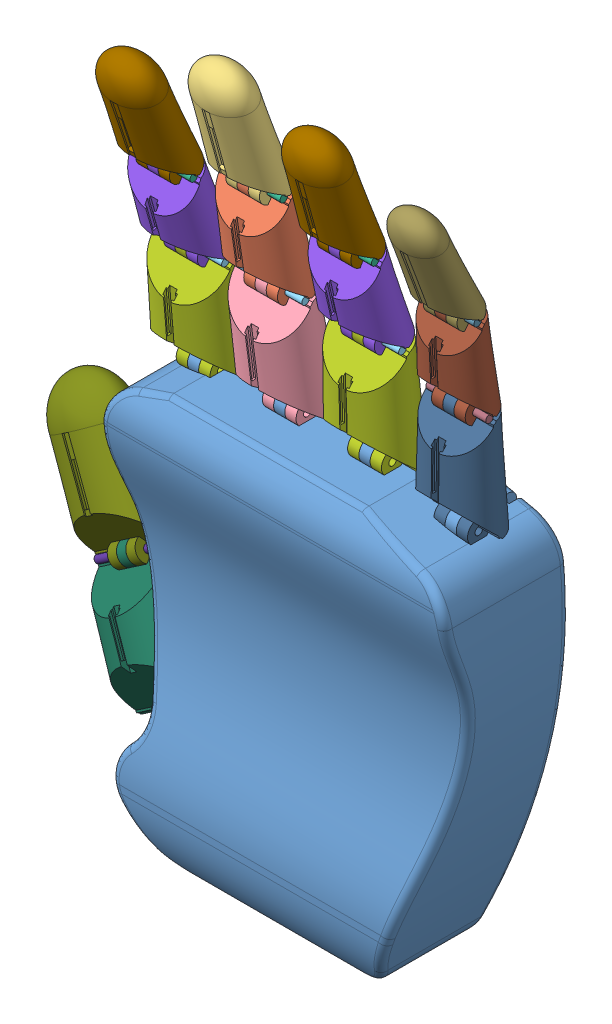
SolidWorks assembly full hand robotic, configuration Default. Lengths in mm.
Overall size (150.83 204.79 69.19).
29 component instances, 17 part files, 10 mates.
Components (placement in the parent):
- THE PALM OF THE HAND-1: THE PALM OF THE HAND [Default] at (36.8202 51.8286 92.09) size (102.61 115 45.25)
- finger-1: finger [Default] at (0.6949 107.2113 93.163) x (0.37395 0.005 -0.927435) z (0.854534 -0.390511 0.34245) size (39.48 95 52.05)
  - part12-1: part12 [Default] at (-1.7536 63.4783 2.9462) x (-0.37395 -0.360461 -0.854534) z (-0.912407 -0.022287 0.408677) size (20.07 32 15.01)
  - part13-1: part13 [Default] at (-8.8406 87.4834 -4.0784) x (-0.37395 -0.360461 -0.854534) z (-0.885847 -0.134042 0.444194) size (18.07 36.5 13.01)
  - part 11-2: part 11 [Default] at (2.5604 39.2329 11.2856) x (-0.37395 -0.360461 -0.854534) z (-0.916242 0.000782 0.400624) size (22.08 37 17.01)
  - mate1-1: mate1 [Default] at (-0.877 36.4552 3.4295) x (-0.919414 0.265096 0.290519) z (0.37395 0.360461 0.854534) size (2 2 18)
  - mate2-1: mate2 [Default] at (-4.8284 61.0608 -4.0504) x (-0.079899 -0.905435 0.416897) z (0.37395 0.360461 0.854534) size (2 2 16)
- Assem1 index and ring-1: Assem1 index and ring [Default] at (-0.6374 69.6197 84.5519) x (0.950377 -0.279853 -0.135886) z (0.054985 -0.278814 0.95877) size (46.69 90.74 23.77)
  - part 1 ind-1: part 1 ind [Default] at (-17.4645 65.0369 -4.3815) x (-0.950377 -0.306201 -0.054985) z (-0.102598 0.141635 0.984588) size (22.08 35 17.01)
  - part 2 ind-1: part 2 ind [Default] at (-24.8544 87.8504 -3.6973) x (-0.950377 -0.306201 -0.054985) z (-0.042281 -0.047975 0.997953) size (20.07 30 15.01)
  - part 3 ind-1: part 3 ind [Default] at (-32.2884 110.5966 -1.8742) x (-0.950377 -0.306201 -0.054985) z (-0.028567 -0.090104 0.995523) size (18.07 34.5 13.01)
  - mate1-1: mate1 [Default] at (-26.1648 62.7518 -4.9594) x (0.143858 -0.27584 -0.950377) z (0.950377 0.306201 0.054985) size (2 2 18)
  - mate2-1: mate2 [Default] at (-32.6115 85.8762 -4.1209) x (0.143858 -0.27584 -0.950377) z (0.950377 0.306201 0.054985) size (2 2 16)
- Assem1 index and ring-2: Assem1 index and ring [Default] at (45.1265 70.7609 86.4924) x (0.950377 -0.286452 -0.121359) z (0.054985 -0.229291 0.971804) size (46.69 90.74 23.77)
  - part 1 ind-1: part 1 ind [Default] at (-17.4645 65.0369 -4.3815) x (-0.950377 -0.306201 -0.054985) z (-0.102598 0.141635 0.984588) size (22.08 35 17.01)
  - part 2 ind-1: part 2 ind [Default] at (-24.8544 87.8504 -3.6973) x (-0.950377 -0.306201 -0.054985) z (-0.042281 -0.047975 0.997953) size (20.07 30 15.01)
  - part 3 ind-1: part 3 ind [Default] at (-32.2884 110.5966 -1.8742) x (-0.950377 -0.306201 -0.054985) z (-0.028567 -0.090104 0.995523) size (18.07 34.5 13.01)
  - mate1-1: mate1 [Default] at (-26.1648 62.7518 -4.9594) x (0.143858 -0.27584 -0.950377) z (0.950377 0.306201 0.054985) size (2 2 18)
  - mate2-1: mate2 [Default] at (-32.6115 85.8762 -4.1209) x (0.143858 -0.27584 -0.950377) z (0.950377 0.306201 0.054985) size (2 2 16)
- Assem2 pinky-1: Assem2 pinky [Default] at (68.0239 86.0386 65.5036) x (0.983786 -0.156121 0.088267) z (-0.139093 -0.353492 0.925039) size (30.65 84.82 33.05)
  - part 1 pinky-1: part 1 pinky [Default] at (-1.3014 53.9301 11.8427) x (-0.983786 -0.113216 0.139093) z (0.091703 0.34896 0.93264) size (20.08 34 15.01)
  - part 2 pinky-1: part 2 pinky [Default] at (-4.6872 75.8419 5.7312) x (-0.983786 -0.113216 0.139093) z (0.102667 0.280394 0.954379) size (18.07 29 13.01)
  - part 3 pinky-1: part 3 pinky [Default] at (-7.2345 98.6713 6.2965) x (-0.983786 -0.113216 0.139093) z (0.141692 -0.015201 0.989794) size (16.07 32.5 11.01)
  - mate11-1: mate11 [Default] at (6.4918 55.301 10.5635) x (0.167431 -0.301812 0.93855) z (-0.983786 -0.113216 0.139093) size (2 2 16)
  - mate22-1: mate22 [Default] at (2.1258 77.111 4.6254) x (0.15822 -0.913063 0.375874) z (-0.983786 -0.113216 0.139093) size (2 2 14)
- Assem4 thumb-1: Assem4 thumb [Default] at (-18.8451 21.1376 57.2553) x (0.866872 0.483742 0.120526) z (-0.118864 -0.034233 0.99232) size (34.32 74.41 29.87)
  - part 1 thumb-1: part 1 thumb [Default] at (14.5771 23.6089 32.2095) x (-0.988676 -0.093394 0.117464) z (0.102966 0.147252 0.983725) size (26.08 37 20.01)
  - part 3 thumb-1: part 3 thumb [Default] at (11.8048 49.2961 29.2993) x (-0.988676 -0.093394 0.117464) z (0.105649 0.122719 0.986802) size (24.07 39.51 17.01)
  - mate1 thumb-1: mate1 thumb [Default] at (3.1527 23.0272 33.4924) x (-0.018558 -0.700646 -0.713268) z (0.988676 0.093394 -0.117464) size (2 2 23)
Mates (geometry in assembly coordinates):
- Concentric1: concentric aligned: cylinder of THE PALM OF THE HAND-1 through (26.9382 108.8286 95.6606) axis (-1 0 0) radius 1; cylinder of finger-1/part 11-2 through (36.4494 108.8286 95.6606) axis (-1 0 0) radius 1
- Coincident1: coincident anti-aligned: plane of THE PALM OF THE HAND-1 through (23.9382 108.8286 95.6606) normal (-1 0 0); plane of finger-1/part 11-2 through (23.9382 108.8286 95.6606) normal (1 0 0)
- Concentric2: concentric anti-aligned: cylinder of THE PALM OF THE HAND-1 through (46.7021 108.8286 95.6606) axis (1 0 0) radius 1; cylinder of Assem1 index and ring-2/part 1 ind-1 through (59.2134 108.8286 95.6606) axis (-1 0 0) radius 1
- Coincident2: coincident anti-aligned: plane of THE PALM OF THE HAND-1 through (46.7021 108.8286 95.6606) normal (-1 0 0); plane of Assem1 index and ring-2/part 1 ind-1 through (46.7021 108.8286 95.6606) normal (1 0 0)
- Concentric3: concentric aligned: cylinder of THE PALM OF THE HAND-1 through (3.9382 107.1673 95.6597) axis (-1 0 0) radius 1; cylinder of Assem1 index and ring-1/part 1 ind-1 through (13.4494 107.1673 95.6597) axis (-1 0 0) radius 1
- Coincident3: coincident anti-aligned: plane of THE PALM OF THE HAND-1 through (0.9382 107.1673 95.6597) normal (-1 0 0); plane of Assem1 index and ring-1/part 1 ind-1 through (0.9382 107.1673 95.6597) normal (1 0 0)
- Concentric4: concentric anti-aligned: cylinder of THE PALM OF THE HAND-1 through (69.7021 104.3029 95.6606) axis (1 0 0) radius 1; cylinder of Assem2 pinky-1/part 1 pinky-1 through (81.2128 104.3029 95.6606) axis (-1 0 0) radius 1
- Coincident4: coincident anti-aligned: plane of THE PALM OF THE HAND-1 through (69.7021 104.3029 95.6606) normal (-1 0 0); plane of Assem2 pinky-1/part 1 pinky-1 through (69.7021 104.3029 95.6606) normal (1 0 0)
- Concentric5: concentric anti-aligned: cylinder of THE PALM OF THE HAND-1 through (-5.7722 22.0914 95.6697) axis (0.825801 0.563962 0) radius 1; cylinder of Assem4 thumb-1/part 1 thumb-1 through (6.2071 30.2724 95.6697) axis (-0.825801 -0.563962 0) radius 1
- Coincident5: coincident anti-aligned: plane of THE PALM OF THE HAND-1 through (-3.2948 23.7833 95.6697) normal (0.825801 0.563962 0); plane of Assem4 thumb-1/part 1 thumb-1 through (-3.2948 23.7833 95.6697) normal (-0.825801 -0.563962 0)
